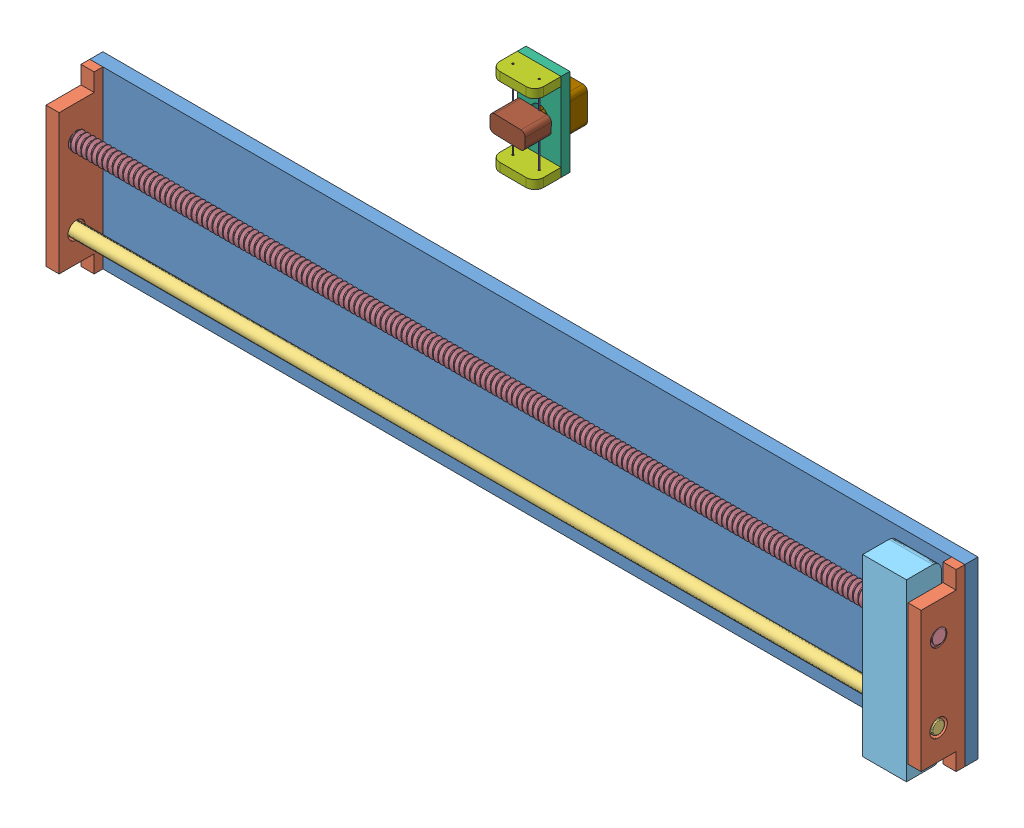
SolidWorks assembly 123, configuration Default. Lengths in mm.
Overall size (1015.13 320.76 217.18).
16 component instances, 12 part files, 12 mates.
Components (placement in the parent):
- x axis base-1: x axis base [Default] at (367.7437 540.8976 757.5659) size (1000 200 15)
- rod holder 2-1: rod holder 2 [Default] at (-117.2563 540.8976 772.5659) x (0 -1 0) z (-1 0 0) size (200 50 15)
- rod holder 2-2: rod holder 2 [Default] at (867.7437 540.8976 772.5659) x (0 -1 0) z (-1 0 0) size (200 50 15)
- Rod-2: Rod [Default] at (-132.3217 494.4435 802.5659) x (0 0 -1) z (1 0 0) size (15 15 1000)
- threaded rod-2: threaded rod [Default] at (867.7171 583.4976 802.5659) x (0 -0.198956 0.980008) z (-1 0 0) size (20.63 23.09 1015.13)
- slider 3-1: slider 3 [Default] at (851.5801 539.4435 769.5827) x (0 -1 0) z (-1 0 0) size (200 40 50)
- pen base-1: pen base [Default] at (219.027 658.2183 556.5848) size (53.53 100.13 79.5)
  - Part1-1: Part1 [Default] at (30.7253 53.4365 74.3924) size (50 100 10)
  - Part2-1: Part2 [Default] at (30.7253 93.4365 99.3924) x (1 0 0) z (0 1 0) size (50 30 10)
  - Part2-2: Part2 [Default] at (30.7253 3.4365 99.3924) x (1 0 0) z (0 1 0) size (50 30 10)
  - nail 2-1: nail 2 [Default] at (15.7253 103.4365 99.3924) x (-0.994111 0 -0.108367) z (0 -1 0) size (1 1 100)
  - nail 2-2: nail 2 [Default] at (45.7253 103.3024 99.3924) x (-0.288518 0 -0.957474) z (0 -1 0) size (1 1 100)
  - servo motor base-1: servo motor base [Default] at (30.7253 53.4365 49.3924) x (0 1 0) z (0 0 1) size (40 40 45)
  - servo part2-1: servo part2 [Default] at (30.7253 53.4365 92.3924) size (25 5 2)
  - Part6-1: Part6 [Default] at (38.9636 62.4912 98.8924) x (0.999564 -0.029543 0) z (0 0 1) size (40 20 30)
  - nail3-2: nail3 [Default] at (23.8224 57.9365 88.8924) size (4 4 10)
Mates (geometry in assembly coordinates):
- Coincident4: coincident: point of x axis base-1; point of rod holder 2-2
- Coincident5: coincident anti-aligned: plane of x axis base-1 through (367.7437 540.8976 772.5659) normal (0 0 1); plane of rod holder 2-2 through (852.7437 440.8976 772.5659) normal (0 0 -1)
- Coincident6: coincident anti-aligned: line of x axis base-1 through (867.7437 440.8976 772.5659) axis (0 1 0); line of rod holder 2-2 through (867.7437 640.8976 772.5659) axis (0 -1 0)
- Concentric3: concentric anti-aligned: cylinder of slider 3-1 through (801.5801 494.4435 802.5659) axis (1 0 0) radius 10; cylinder of Rod-2 through (867.6783 494.4435 802.5659) axis (-1 0 0) radius 7.5
- Coincident7: coincident: point of x axis base-1; point of rod holder 2-1
- Coincident8: coincident: plane of x axis base-1 through (367.7437 540.8976 772.5659) normal (0 0 1); plane of rod holder 2-1 through (-132.2563 440.8976 772.5659) normal (0 0 -1)
- Coincident9: coincident anti-aligned: line of x axis base-1 through (867.7437 640.8976 772.5659) axis (-1 0 0); line of rod holder 2-1 through (-132.2563 640.8976 772.5659) axis (1 0 0)
- Concentric5: concentric aligned: circle of rod holder 2-1; circle of threaded rod-2
- Parallel4: parallel anti-aligned: plane of slider 3-1 through (801.5801 442.9896 783.1542) normal (0 0 -1); plane of x axis base-1 through (367.7437 540.8976 772.5659) normal (0 0 1)
- Parallel6: parallel anti-aligned: plane of slider 3-1 through (801.7426 642.9896 783.1542) normal (0 1 0); plane of pen base-1/servo motor base-1 through (831.7426 642.9896 803.1542) normal (0 -1 0)
- Coincident16: coincident: moEndPointRef_w of slider 3-1; line of pen base-1/servo motor base-1 through (816.7426 642.9896 823.1542) axis (1 0 0)
- Coincident17: coincident aligned: line of slider 3-1 through (851.7426 642.9896 823.1542) axis (0 0 -1); line of pen base-1/servo motor base-1 through (851.7426 642.9896 818.1542) axis (0 0 -1)
